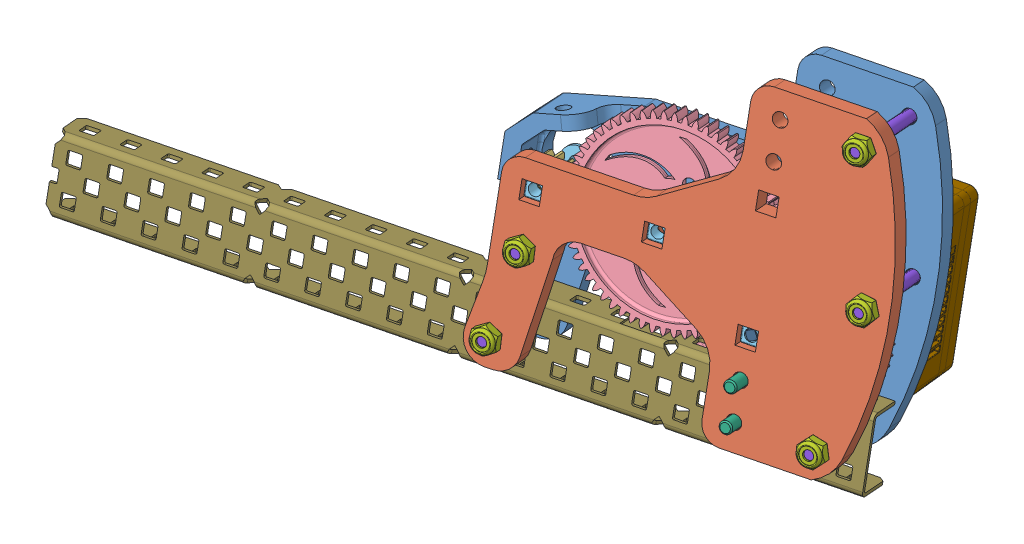
SolidWorks assembly GearBoxAssembly2, configuration Default. Lengths in mm.
Overall size (252.82 140.64 170.44).
28 component instances, 12 part files, 72 mates.
Components (placement in the parent):
- Gearbox with plexi mountwbearing-1: Gearbox with plexi mountwbearing [Default] at (153.245 159.1428 307.4018) x (-0.958945 0.033259 0.281634) z (0.033259 -0.973057 0.228153) size (129.35 17.78 109.22)
- Gearbox-2: Gearbox [Default] at (161.1139 165.5174 333.442) x (-0.958945 0.033259 0.281634) z (0.033259 -0.973057 0.228153) size (125.09 6.35 109.22)
- 12 Tooth Gear-1: 12 Tooth Gear [Default] at (198.2776 168.4603 297.9855) x (-0.933553 0.289602 0.211208) z (0.281634 0.228153 0.932002) size (14.8 14.8 9.53)
- 60 Tooth Gear-1: 60 Tooth Gear [Default] at (200.9602 170.6334 306.8628) x (0.221722 0.929557 -0.294555) z (0.281634 0.228153 0.932002) size (65.54 65.54 9.53)
- 60 Tooth Gear-2: 60 Tooth Gear [Default] at (229.908 147.6142 293.5305) x (-0.481277 0.873888 -0.068494) z (0.281634 0.228153 0.932002) size (65.54 65.54 9.53)
- 12 Tooth Gear-3: 12 Tooth Gear [Default] at (164.4731 171.8989 317.5788) x (0.033259 -0.973057 0.228153) z (0.281634 0.228153 0.932002) size (14.8 14.8 9.53)
- Gear HS Insert Plastic-1: Gear HS Insert Plastic [Default] at (202.3015 171.72 311.3015) x (0.958945 -0.033259 -0.281634) z (0.033259 -0.973057 0.228153) size (10.03 5.08 10.03)
- Gear HS Insert Plastic-2: Gear HS Insert Plastic [Default] at (196.9867 167.3226 293.5441) x (0.958945 -0.033259 -0.281634) z (-0.033259 0.973057 -0.228153) size (10.03 5.08 10.03)
- Gear HS Insert Plastic-3: Gear HS Insert Plastic [Default] at (228.5667 146.5276 289.0918) x (0.958945 -0.033259 -0.281634) z (-0.033259 0.973057 -0.228153) size (10.03 5.08 10.03)
- Gear HS Insert Plastic-4: Gear HS Insert Plastic [Default] at (233.9318 150.8739 306.8465) x (-0.958945 0.033259 0.281634) z (-0.033259 0.973057 -0.228153) size (10.03 5.08 10.03)
- Gear HS Insert Plastic-7: Gear HS Insert Plastic [Default] at (165.7656 172.9871 322.0317) x (-0.958945 0.033259 0.281634) z (-0.033259 0.973057 -0.228153) size (10.03 5.08 10.03)
- Gear HS Insert Plastic-8: Gear HS Insert Plastic [Default] at (160.4492 168.6391 304.2628) x (0.958945 -0.033259 -0.281634) z (-0.033259 0.973057 -0.228153) size (10.03 5.08 10.03)
- Screw 832 .5in-2: Screw 832 .5in [Default] at (234.1593 125.6534 310.6897) x (0.281634 0.228153 0.932002) z (-0.912844 0.362974 0.186989) size (15.36 8.02 7.99)
- Screw 832 .5in-3: Screw 832 .5in [Default] at (234.066 138.2778 308.8811) x (0.281634 0.228153 0.932002) z (-0.912844 0.362974 0.186989) size (15.36 8.02 7.99)
- Nut 832 Nylock-1: Nut 832 Nylock [Default] at (258.2152 216.0045 291.7406) x (0.958945 -0.033259 -0.281634) z (0.033259 -0.973057 0.228153) size (10.2 4.9 8.12)
- Nut 832 Nylock-2: Nut 832 Nylock [Default] at (267.6518 171.2417 299.8468) x (0.953063 -0.179024 -0.244173) z (-0.111142 -0.957025 0.267863) size (10.2 4.9 8.12)
- Nut 832 Nylock-3: Nut 832 Nylock [Default] at (261.2563 127.0281 312.6029) x (0.939861 -0.261214 -0.220064) z (-0.193243 -0.937931 0.287999) size (10.2 4.9 8.12)
- Screw 832 1.5in-1: Screw 832 1.5in [Default] at (247.9356 207.6769 257.7227) x (0.281634 0.228153 0.932002) z (-0.958945 0.033259 0.281634) size (40.76 8.02 7.99)
- Screw 832 1.5in-2: Screw 832 1.5in [Default] at (257.3723 162.9142 265.8289) x (0.281634 0.228153 0.932002) z (-0.958945 0.033259 0.281634) size (40.76 8.02 7.99)
- Screw 832 1.5in-3: Screw 832 1.5in [Default] at (250.9767 118.7006 278.585) x (0.281634 0.228153 0.932002) z (-0.958945 0.033259 0.281634) size (40.76 8.02 7.99)
- V5_Smart_Motor_276-4840-1: V5_Smart_Motor_276-4840 [Default] at (214.3713 122.323 243.706) x (-0.033259 0.973057 -0.228153) z (0.281634 0.228153 0.932002) size (57.3 33 72.3)
- Screw 832 1.5in-4: Screw 832 1.5in [Default] at (158.2275 149.6895 299.026) x (0.281634 0.228153 0.932002) z (-0.958945 0.033259 0.281634) size (40.76 8.02 7.99)
- Nut 832 Nylock-4: Nut 832 Nylock [Default] at (168.5071 158.017 333.0439) x (0.862544 -0.485723 -0.141741) z (-0.420357 -0.843812 0.333588) size (10.2 4.9 8.12)
- Shaft 2in-1: Shaft 2in [Default] at (228.2418 146.2267 287.901) x (-0.830093 -0.429261 0.355922) z (0.281634 0.228153 0.932002) size (4.18 4.18 51.01)
- Shaft 1in-1: Shaft 1in [Default] at (195.5345 166.2307 288.7996) x (-0.221722 -0.929557 0.294555) z (0.281634 0.228153 0.932002) size (4.18 4.18 25.5)
- Channel 121-CUSTOM2 Aluminum-1: Channel 121-CUSTOM2 Aluminum [Default] at (-7.4609 131.9622 384.5295) x (0.958945 -0.033259 -0.281634) z (0.033259 -0.973057 0.228153) size (254 13.87 25.4)
- Screw 832 1.5in-5: Screw 832 1.5in [Default] at (153.5479 122.0797 307.199) x (0.281634 0.228153 0.932002) z (-0.958945 0.033259 0.281634) size (40.76 8.02 7.99)
- Nut 832 Nylock-5: Nut 832 Nylock [Default] at (163.8275 130.4072 341.2169) x (0.862544 -0.485723 -0.141741) z (-0.420357 -0.843812 0.333588) size (10.2 4.9 8.12)
Mates (geometry in assembly coordinates):
- Tangent1: tangent: plane of ? through (245.9781 119.1391 277.957) normal (1 0 0); cylinder of Gearbox with plexi mountwbearing-1 through (248.3911 121.5521 269.067) axis (0 0 1) radius 2.413
- Coincident1: coincident: plane of ? through (-56.5105 134.1505 275.417) normal (0 0 -1); plane of Gearbox with plexi mountwbearing-1
- Parallel1: parallel: plane of ? through (-56.5105 108.7505 276.5854) normal (0 -1 0); plane of Gearbox with plexi mountwbearing-1
- Tangent2: tangent: plane of ? through (245.9781 119.1391 277.957) normal (0 1 0); cylinder of Gearbox with plexi mountwbearing-1 through (248.3911 121.5521 269.067) axis (0 0 1) radius 2.413
- Coincident4: coincident: plane of Gearbox with plexi mountwbearing-1 through (149.3181 220.2632 286.813) normal (-0.033259 0.973057 -0.228153); plane of Gearbox-2 through (157.1869 226.6378 312.8531) normal (-0.033259 0.973057 -0.228153)
- Coincident8: coincident: plane of 12 Tooth Gear-1 through (199.6189 169.5468 302.4242) normal (0.281634 0.228153 0.932002); plane of 60 Tooth Gear-1 through (199.6189 169.5468 302.4242) normal (-0.281634 -0.228153 -0.932002)
- Concentric1: concentric: circle of 12 Tooth Gear-1; circle of 60 Tooth Gear-1
- Coincident9: coincident: plane of Gearbox-2 through (158.8976 176.5886 324.5882) normal (0.033259 -0.973057 0.228153); plane of Gear HS Insert Plastic-1 through (200.6071 176.0485 316.2045) normal (-0.033259 0.973057 -0.228153)
- Coincident10: coincident: plane of Gearbox-2 through (199.962 162.6592 315.5892) normal (0.958945 -0.033259 -0.281634); plane of Gear HS Insert Plastic-1 through (200.6071 176.0485 316.2045) normal (-0.958945 0.033259 0.281634)
- Coincident11: coincident: plane of Gearbox-2 through (159.3255 164.0686 327.5237) normal (-0.281634 -0.228153 -0.932002); plane of Gear HS Insert Plastic-1 through (202.6591 172.0097 312.4851) normal (0.281634 0.228153 0.932002)
- Concentric2: concentric: cylinder of 60 Tooth Gear-1 through (199.3524 169.331 301.5424) axis (0.281634 0.228153 0.932002) radius 4; cylinder of Gear HS Insert Plastic-1 through (202.6591 172.0097 312.4851) axis (-0.281634 -0.228153 -0.932002) radius 5.0165
- Coincident12: coincident: plane of 60 Tooth Gear-1 through (202.3015 171.72 311.3015) normal (0.281634 0.228153 0.932002); plane of Gear HS Insert Plastic-1 through (202.3015 171.72 311.3015) normal (-0.281634 -0.228153 -0.932002)
- Coincident13: coincident: plane of Gearbox with plexi mountwbearing-1 through (198.1825 156.0734 287.7606) normal (-0.958945 0.033259 0.281634); plane of Gear HS Insert Plastic-2 through (198.6811 162.994 288.6411) normal (0.958945 -0.033259 -0.281634)
- Coincident14: coincident: plane of Gearbox with plexi mountwbearing-1 through (153.245 159.1428 307.4018) normal (0.281634 0.228153 0.932002); plane of Gear HS Insert Plastic-2 through (196.6291 167.0328 292.3605) normal (-0.281634 -0.228153 -0.932002)
- Coincident15: coincident: plane of Gearbox with plexi mountwbearing-1 through (151.2399 164.0351 299.9968) normal (-0.033259 0.973057 -0.228153); plane of Gear HS Insert Plastic-2 through (192.6405 163.2035 290.4152) normal (0.033259 -0.973057 0.228153)
- Distance1: distance = 21.59 mm: plane of Gearbox-2 through (159.3255 164.0686 327.5237) normal (-0.281634 -0.228153 -0.932002); plane of Gearbox with plexi mountwbearing-1 through (153.245 159.1428 307.4018) normal (0.281634 0.228153 0.932002)
- Concentric4: concentric: cylinder of V5_Smart_Motor_276-4840-1 through (227.439 120.2092 288.4504) axis (0.281634 0.228153 0.932002) radius 1.7272; cylinder of Gearbox-2 through (235.1107 126.4241 313.8382) axis (0.281634 0.228153 0.932002) radius 2.413
- Coincident18: coincident: plane of Gearbox with plexi mountwbearing-1 through (151.7046 150.4415 303.1841) normal (0.033259 -0.973057 0.228153); plane of Gear HS Insert Plastic-3 through (224.0109 148.538 284.5257) normal (-0.033259 0.973057 -0.228153)
- Coincident19: coincident: plane of Gearbox with plexi mountwbearing-1 through (153.245 159.1428 307.4018) normal (0.281634 0.228153 0.932002); plane of Gear HS Insert Plastic-3 through (228.209 146.2378 287.9082) normal (-0.281634 -0.228153 -0.932002)
- Coincident20: coincident: plane of Gearbox-2 through (159.3255 164.0686 327.5237) normal (-0.281634 -0.228153 -0.932002); plane of Gear HS Insert Plastic-4 through (234.2895 151.1636 308.0301) normal (0.281634 0.228153 0.932002)
- Coincident21: coincident: plane of Gearbox-2 through (159.5734 156.8161 329.2242) normal (0.033259 -0.973057 0.228153); plane of Gear HS Insert Plastic-4 through (238.2781 154.9929 309.9754) normal (-0.033259 0.973057 -0.228153)
- Concentric6: concentric: cylinder of Gear HS Insert Plastic-4 through (233.9318 150.8739 306.8465) axis (-0.281634 -0.228153 -0.932002) radius 2.032; cylinder of 60 Tooth Gear-2 through (228.3002 146.3117 288.2101) axis (0.281634 0.228153 0.932002) radius 4
- Coincident24: coincident: plane of Gear HS Insert Plastic-3 through (228.5667 146.5276 289.0918) normal (0.281634 0.228153 0.932002); plane of 60 Tooth Gear-2 through (228.5667 146.5276 289.0918) normal (-0.281634 -0.228153 -0.932002)
- Coincident25: coincident: plane of Gearbox-2 through (163.4262 163.9264 326.3194) normal (0.958945 -0.033259 -0.281634); plane of Gear HS Insert Plastic-7 through (164.2808 171.1862 328.3719) normal (-0.958945 0.033259 0.281634)
- Coincident26: coincident: plane of Gearbox-2 through (158.8976 176.5886 324.5882) normal (0.033259 -0.973057 0.228153); plane of Gear HS Insert Plastic-7 through (170.1119 177.1061 325.1607) normal (-0.033259 0.973057 -0.228153)
- Coincident27: coincident: plane of Gearbox-2 through (159.3255 164.0686 327.5237) normal (-0.281634 -0.228153 -0.932002); plane of Gear HS Insert Plastic-7 through (166.1233 173.2769 323.2154) normal (0.281634 0.228153 0.932002)
- Coincident31: coincident: plane of Gearbox with plexi mountwbearing-1 through (153.245 159.1428 307.4018) normal (0.281634 0.228153 0.932002); plane of Gear HS Insert Plastic-8 through (160.0915 168.3494 303.0792) normal (-0.281634 -0.228153 -0.932002)
- Concentric7: concentric: cylinder of 12 Tooth Gear-3 through (163.1318 170.8123 313.1401) axis (0.281634 0.228153 0.932002) radius 3.25; cylinder of Gear HS Insert Plastic-8 through (160.4492 168.6391 304.2628) axis (0.281634 0.228153 0.932002) radius 2.032
- Coincident32: coincident: plane of 12 Tooth Gear-3 through (165.8144 172.9855 322.0174) normal (0.281634 0.228153 0.932002); plane of Gear HS Insert Plastic-7 through (165.7656 172.9871 322.0317) normal (-0.281634 -0.228153 -0.932002)
- Concentric8: concentric: cylinder of Screw 832 .5in-2 through (234.1593 125.6534 310.6897) axis (-0.281634 -0.228153 -0.932002) radius 2.0828; cylinder of Gearbox-2 through (235.1107 126.4241 313.8382) axis (0.281634 0.228153 0.932002) radius 2.413
- Coincident33: coincident: plane of Channel 121-CUSTOM2 Aluminum-1 through (-32.5136 123.307 394.2188) normal (-0.281634 -0.228153 -0.932002); plane of Screw 832 .5in-2 through (235.3974 128.0392 312.1025) normal (0.281634 0.228153 0.932002)
- Coincident34: coincident: plane of Gearbox-2 through (159.3255 164.0686 327.5237) normal (-0.281634 -0.228153 -0.932002); plane of Screw 832 .5in-3 through (235.3041 140.6636 310.2939) normal (0.281634 0.228153 0.932002)
- Concentric10: concentric: cylinder of Screw 832 .5in-3 through (234.066 138.2778 308.8811) axis (-0.281634 -0.228153 -0.932002) radius 2.0828; cylinder of Gearbox-2 through (234.6884 138.7819 310.9406) axis (0.281634 0.228153 0.932002) radius 2.413
- Concentric12: concentric: cylinder of Gearbox with plexi mountwbearing-1 through (248.5579 208.1811 259.7822) axis (0.281634 0.228153 0.932002) radius 2.413; cylinder of Screw 832 1.5in-1 through (247.9356 207.6769 257.7227) axis (-0.281634 -0.228153 -0.932002) radius 2.0828
- Coincident35: coincident: plane of Gearbox with plexi mountwbearing-1 through (151.4567 157.694 301.4836) normal (-0.281634 -0.228153 -0.932002); plane of Screw 832 1.5in-1 through (248.4887 210.2078 259.307) normal (0.281634 0.228153 0.932002)
- Concentric13: concentric: cylinder of Screw 832 1.5in-1 through (247.9356 207.6769 257.7227) axis (-0.281634 -0.228153 -0.932002) radius 2.0828; cylinder of Nut 832 Nylock-1 through (258.2152 216.0045 291.7406) axis (0.281634 0.228153 0.932002) radius 1.6955
- Coincident36: coincident: plane of Gearbox-2 through (161.1139 165.5174 333.442) normal (0.281634 0.228153 0.932002); plane of Nut 832 Nylock-1 through (260.5971 211.9774 292.0066) normal (-0.281634 -0.228153 -0.932002)
- Concentric14: concentric: cylinder of Gearbox with plexi mountwbearing-1 through (257.9946 163.4184 267.8885) axis (0.281634 0.228153 0.932002) radius 2.413; cylinder of Screw 832 1.5in-2 through (257.3723 162.9142 265.8289) axis (-0.281634 -0.228153 -0.932002) radius 2.0828
- Coincident37: coincident: plane of Gearbox with plexi mountwbearing-1 through (151.4567 157.694 301.4836) normal (-0.281634 -0.228153 -0.932002); plane of Screw 832 1.5in-2 through (257.9253 165.4451 267.4133) normal (0.281634 0.228153 0.932002)
- Concentric15: concentric: cylinder of Screw 832 1.5in-2 through (257.3723 162.9142 265.8289) axis (-0.281634 -0.228153 -0.932002) radius 2.0828; cylinder of Nut 832 Nylock-2 through (267.6518 171.2417 299.8468) axis (0.281634 0.228153 0.932002) radius 1.6955
- Coincident38: coincident: plane of Gearbox-2 through (161.1139 165.5174 333.442) normal (0.281634 0.228153 0.932002); plane of Nut 832 Nylock-2 through (269.434 166.9382 300.3618) normal (-0.281634 -0.228153 -0.932002)
- Concentric16: concentric: cylinder of Gearbox with plexi mountwbearing-1 through (251.5991 119.2048 280.6445) axis (0.281634 0.228153 0.932002) radius 2.413; cylinder of Screw 832 1.5in-3 through (250.9767 118.7006 278.585) axis (-0.281634 -0.228153 -0.932002) radius 2.0828
- Coincident39: coincident: plane of Gearbox with plexi mountwbearing-1 through (151.4567 157.694 301.4836) normal (-0.281634 -0.228153 -0.932002); plane of Screw 832 1.5in-3 through (251.5298 121.2314 280.1693) normal (0.281634 0.228153 0.932002)
- Concentric17: concentric: cylinder of Nut 832 Nylock-3 through (261.2563 127.0281 312.6029) axis (0.281634 0.228153 0.932002) radius 1.6955; cylinder of Screw 832 1.5in-3 through (250.9767 118.7006 278.585) axis (-0.281634 -0.228153 -0.932002) radius 2.0828
- Coincident40: coincident: plane of Gearbox-2 through (161.1139 165.5174 333.442) normal (0.281634 0.228153 0.932002); plane of Nut 832 Nylock-3 through (262.6743 122.6095 313.256) normal (-0.281634 -0.228153 -0.932002)
- Concentric18: concentric: cylinder of Gearbox with plexi mountwbearing-1 through (158.8499 150.1937 301.0856) axis (0.281634 0.228153 0.932002) radius 2.413; cylinder of Screw 832 1.5in-4 through (158.2275 149.6895 299.026) axis (-0.281634 -0.228153 -0.932002) radius 2.0828
- Coincident41: coincident: plane of Gearbox with plexi mountwbearing-1 through (151.4567 157.694 301.4836) normal (-0.281634 -0.228153 -0.932002); plane of Screw 832 1.5in-4 through (158.7806 152.2204 300.6104) normal (0.281634 0.228153 0.932002)
- Concentric19: concentric: cylinder of Screw 832 1.5in-4 through (158.2275 149.6895 299.026) axis (-0.281634 -0.228153 -0.932002) radius 2.0828; cylinder of Nut 832 Nylock-4 through (168.5071 158.017 333.0439) axis (0.281634 0.228153 0.932002) radius 1.6955
- Coincident42: coincident: plane of Gearbox-2 through (161.1139 165.5174 333.442) normal (0.281634 0.228153 0.932002); plane of Nut 832 Nylock-4 through (168.8222 153.4543 334.0657) normal (-0.281634 -0.228153 -0.932002)
- Coincident46: coincident: plane of 60 Tooth Gear-2 through (230.955 146.8167 299.5413) normal (-0.481277 0.873888 -0.068494); plane of Shaft 2in-1 through (237.4771 151.3159 311.1176) normal (0.481277 -0.873888 0.068494)
- Coincident47: coincident: plane of 60 Tooth Gear-2 through (233.6321 148.2011 298.3934) normal (-0.830093 -0.429261 0.355922); plane of Shaft 2in-1 through (235.949 154.0905 310.9001) normal (0.830093 0.429261 -0.355922)
- GearMate3: gear = 304.8 : 1524 mm: cylinder of 60 Tooth Gear-2 through (229.0138 146.8898 290.5714) axis (0.281634 0.228153 0.932002) radius 32.8041; cylinder of 12 Tooth Gear-1 through (197.3834 167.7359 295.0264) axis (0.281634 0.228153 0.932002) radius 7.404
- Coincident49: coincident: plane of 12 Tooth Gear-1 through (201.75 170.7961 302.4964) normal (-0.221722 -0.929557 0.294555); plane of 60 Tooth Gear-1 through (204.4326 172.9692 311.3737) normal (-0.221722 -0.929557 0.294555)
- Coincident50: coincident: plane of 12 Tooth Gear-1 through (198.7393 171.73 303.1775) normal (0.933553 -0.289602 -0.211208); plane of 60 Tooth Gear-1 through (201.4219 173.9032 312.0548) normal (0.933553 -0.289602 -0.211208)
- GearMate5: gear = 1524 : 304.8 mm: cylinder of 12 Tooth Gear-3 through (163.5789 171.1745 314.6197) axis (0.281634 0.228153 0.932002) radius 7.404; cylinder of 60 Tooth Gear-1 through (200.066 169.909 303.9037) axis (0.281634 0.228153 0.932002) radius 32.8041
- Coincident51: coincident: plane of Gear HS Insert Plastic-2 through (192.431 169.333 288.978) normal (-0.281634 -0.228153 -0.932002); plane of Shaft 1in-1 through (195.5345 166.2307 288.7996) normal (-0.281634 -0.228153 -0.932002)
- Coincident52: coincident: plane of 12 Tooth Gear-1 through (201.035 167.7983 303.4463) normal (-0.933553 0.289602 0.211208); plane of Shaft 1in-1 through (204.522 173.0417 311.6696) normal (0.933553 -0.289602 -0.211208)
- Coincident53: coincident: plane of 12 Tooth Gear-1 through (201.75 170.7961 302.4964) normal (-0.221722 -0.929557 0.294555); plane of Shaft 1in-1 through (201.558 173.9612 312.3402) normal (0.221722 0.929557 -0.294555)
- Concentric25: concentric: cylinder of Gearbox-2 through (234.6884 138.7819 310.9406) axis (0.281634 0.228153 0.932002) radius 2.413; cylinder of V5_Smart_Motor_276-4840-1 through (227.0167 132.5671 285.5529) axis (0.281634 0.228153 0.932002) radius 1.7272
- Coincident54: coincident: plane of Gearbox-2 through (236.9571 161.3761 304.724) normal (-0.958945 0.033259 0.281634); plane of Gear HS Insert Plastic-4 through (238.4876 148.8634 311.4126) normal (0.958945 -0.033259 -0.281634)
- Coincident55: coincident: plane of Gearbox with plexi mountwbearing-1 through (229.0883 155.0015 278.6838) normal (-0.958945 0.033259 0.281634); plane of Gear HS Insert Plastic-3 through (230.261 142.1991 284.1888) normal (0.958945 -0.033259 -0.281634)
- Coincident56: coincident: plane of Gearbox-2 through (159.3255 164.0686 327.5237) normal (-0.281634 -0.228153 -0.932002); plane of Channel 121-CUSTOM2 Aluminum-1 through (-32.1846 123.5736 395.3077) normal (0.281634 0.228153 0.932002)
- Tangent4: tangent: cylinder of Screw 832 1.5in-3 through (250.9767 118.7006 278.585) axis (-0.281634 -0.228153 -0.932002) radius 2.0828; plane of Channel 121-CUSTOM2 Aluminum-1 through (256.6708 127.5407 304.3244) normal (0.958945 -0.033259 -0.281634)
- Tangent5: tangent: cylinder of Screw 832 1.5in-3 through (250.9767 118.7006 278.585) axis (-0.281634 -0.228153 -0.932002) radius 2.0828; plane of Channel 121-CUSTOM2 Aluminum-1 through (256.8246 123.0424 305.3791) normal (-0.033259 0.973057 -0.228153)
- Parallel7: parallel: plane of Gearbox-2 through (160.8194 120.3605 337.772) normal (0.033259 -0.973057 0.228153); plane of Channel 121-CUSTOM2 Aluminum-1 through (-32.5136 123.307 394.2188) normal (0.033259 -0.973057 0.228153)
- Concentric26: concentric: cylinder of Gearbox with plexi mountwbearing-1 through (154.1703 122.5838 309.2585) axis (0.281634 0.228153 0.932002) radius 2.413; cylinder of Screw 832 1.5in-5 through (153.5479 122.0797 307.199) axis (-0.281634 -0.228153 -0.932002) radius 2.0828
- Coincident58: coincident: plane of Gearbox with plexi mountwbearing-1 through (151.4567 157.694 301.4836) normal (-0.281634 -0.228153 -0.932002); plane of Screw 832 1.5in-5 through (154.101 124.6105 308.7833) normal (0.281634 0.228153 0.932002)
- Concentric27: concentric: cylinder of Screw 832 1.5in-5 through (153.5479 122.0797 307.199) axis (-0.281634 -0.228153 -0.932002) radius 2.0828; cylinder of Nut 832 Nylock-5 through (163.8275 130.4072 341.2169) axis (0.281634 0.228153 0.932002) radius 1.6955
- Coincident59: coincident: plane of Gearbox-2 through (161.1139 165.5174 333.442) normal (0.281634 0.228153 0.932002); plane of Nut 832 Nylock-5 through (164.1426 125.8445 342.2386) normal (-0.281634 -0.228153 -0.932002)
- Coincident60: coincident: plane of Gearbox with plexi mountwbearing-1 through (151.4567 157.694 301.4836) normal (-0.281634 -0.228153 -0.932002); plane of V5_Smart_Motor_276-4840-1 through (226.8195 132.4074 284.9005) normal (0.281634 0.228153 0.932002)
- Coincident61: coincident: plane of Gear HS Insert Plastic-4 through (238.2781 154.9929 309.9754) normal (0.281634 0.228153 0.932002); plane of Shaft 2in-1 through (237.4771 151.3159 311.1176) normal (0.281634 0.228153 0.932002)
- Parallel8: parallel: plane of Gearbox-2 through (158.8976 176.5886 324.5882) normal (0.033259 -0.973057 0.228153); plane of 12 Tooth Gear-3 through (167.5753 174.7182 322.0831) normal (0.033259 -0.973057 0.228153)
